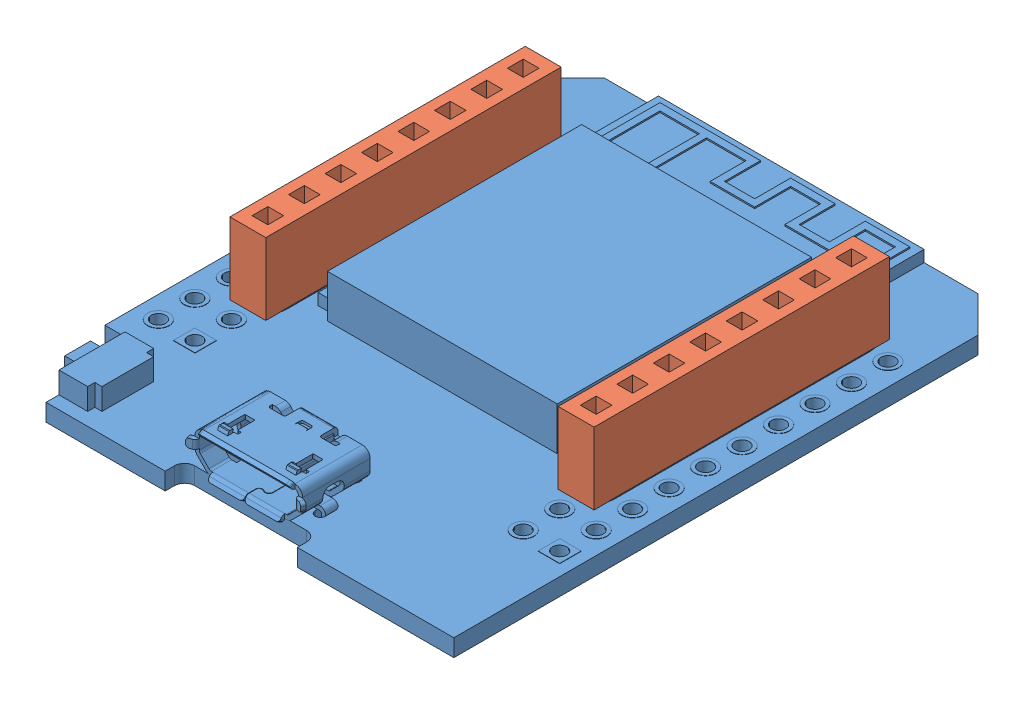
SolidWorks assembly MH-ET Live ESP32 MiniKIT - headers f short, configuration Default. Lengths in mm.
Overall size (31 8 39).
3 component instances, 2 part files, 9 mates.
Components (placement in the parent):
- MH-ET Live ESP32 MiniKIT-1: MH-ET Live ESP32 MiniKIT [Default] at (137.257 -40.9796 -63.0415) size (31 4.62 39)
- header_f8_short-1: header_f8_short [Default] at (11.43 1.2 -33.155) x (0 0 1) z (-1 0 0) size (20.57 8 2.5)
- header_f8_short-2: header_f8_short [Default] at (-11.43 1.2 -33.155) x (0 0 1) z (-1 0 0) size (20.57 8 2.5)
Mates (geometry in assembly coordinates):
- Coincident4: coincident aligned: plane of MH-ET Live ESP32 MiniKIT-1 through (137.257 -40.9796 0) normal (0 0 1)
- Coincident5: coincident aligned: plane of MH-ET Live ESP32 MiniKIT-1 through (137.257 0 -63.0415) normal (0 1 0)
- Coincident6: coincident aligned: plane of MH-ET Live ESP32 MiniKIT-1 through (0 -40.9796 -63.0415) normal (1 0 0)
- Coincident7: coincident anti-aligned: plane of MH-ET Live ESP32 MiniKIT-1 through (-14.1 1.2 -5.5) normal (0 1 0); plane of header_f8_short-1 through (10.18 1.2 -33.155) normal (0 -1 0)
- Coincident8: coincident anti-aligned: plane of MH-ET Live ESP32 MiniKIT-1 through (-14.1 1.2 -5.5) normal (0 1 0); plane of header_f8_short-2 through (-12.68 1.2 -33.155) normal (0 -1 0)
- Coincident9: coincident anti-aligned: line of MH-ET Live ESP32 MiniKIT-1 through (11.43 -0.02 -31.76) axis (0 1 0); line of header_f8_short-1 through (11.43 1.2 -31.76) axis (0 -1 0)
- Coincident10: coincident anti-aligned: line of MH-ET Live ESP32 MiniKIT-1 through (-11.43 -0.0395 -31.76) axis (0 1 0); line of header_f8_short-2 through (-11.43 1.2 -31.76) axis (0 -1 0)
- Parallel2: parallel anti-aligned: plane of MH-ET Live ESP32 MiniKIT-1 through (0 -40.9796 -63.0415) normal (1 0 0); plane of header_f8_short-2 through (-11.43 1.2 -33.155) normal (-1 0 0)
- Parallel3: parallel anti-aligned: plane of MH-ET Live ESP32 MiniKIT-1 through (0 -40.9796 -63.0415) normal (1 0 0); plane of header_f8_short-1 through (11.43 1.2 -33.155) normal (-1 0 0)
